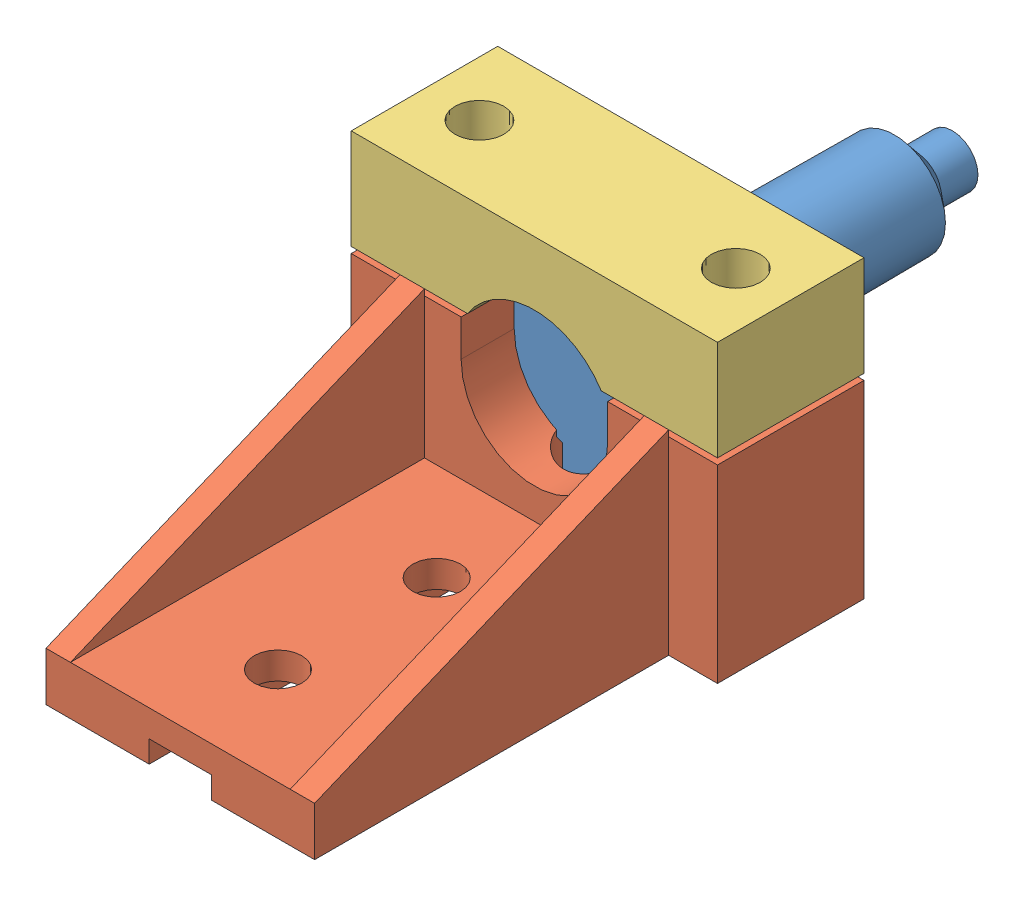
SolidWorks assembly purplecolumnholder, configuration Default. Lengths in mm.
Overall size (30 24.2 63.24).
3 component instances, 3 part files, 2 mates.
Components (placement in the parent):
- qiagen_purple_column-1: qiagen_purple_column [Default] at (-11.6823 35.6853 -59.7928) x (-1 0 0) z (0 0 -1) size (12.93 19.03 29.89)
- purpleColumnHolder-1: purpleColumnHolder [Default] at (-21.4017 -1.8147 -25.5562) size (30 16 41)
- purplecolumnclamper-1: purplecolumnclamper [Default] at (0 39.1853 0) x (1 0 0) z (0 1 0) size (30 12 9.39)
Mates (geometry in assembly coordinates):
- Concentric2: concentric aligned: cylinder of qiagen_purple_column-1 through (-11.6823 35.6853 -31.1728) axis (0 0 1) radius 2.1; cylinder of purpleColumnHolder-1 through (-11.6823 35.6853 -37.5562) axis (0 0 1) radius 4.5
- Parallel2: parallel aligned: plane of qiagen_purple_column-1 through (-9.6523 26.0922 -30.4963) normal (1 0 0); plane of purpleColumnHolder-1 through (3.3177 39.1853 -37.5562) normal (1 0 0)
